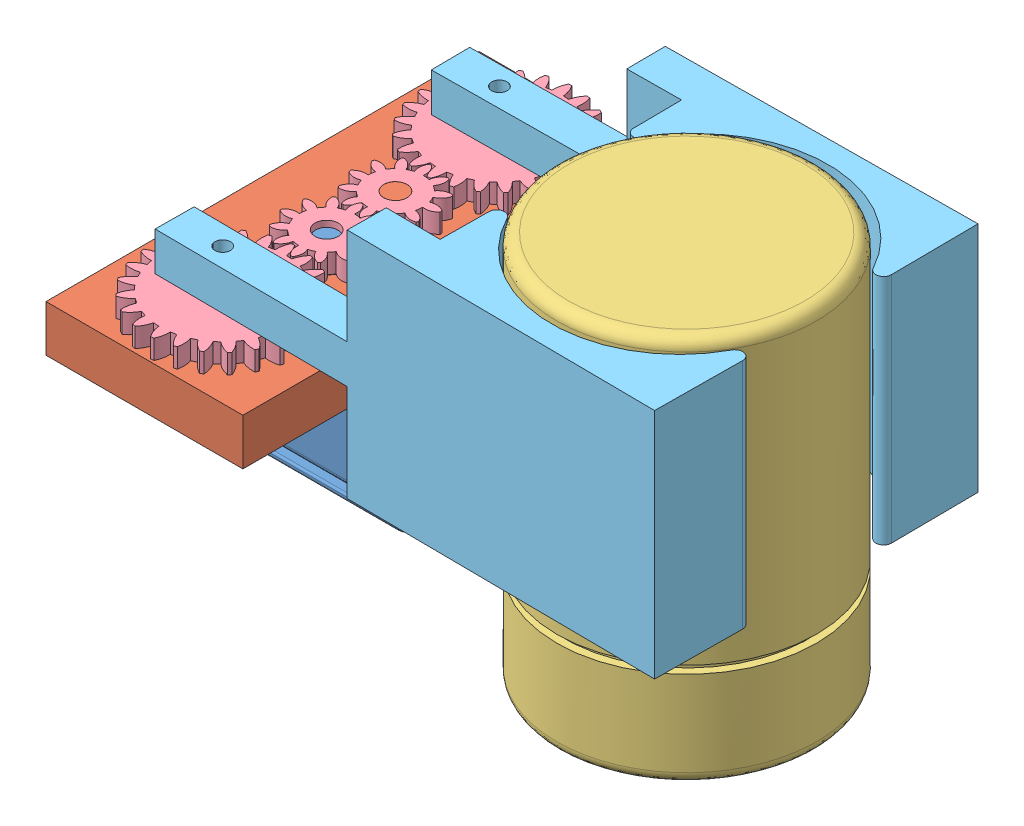
SolidWorks assembly Assembly, configuration Default. Lengths in mm.
Overall size (143.71 100 123.27).
9 component instances, 5 part files, 15 mates.
Components (placement in the parent):
- servo-1: servo [Default] at (15.8776 33.6405 0.8899) size (56.4 46.15 25.5)
- support_base_v2-1: support_base_v2 [Default] at (16.1776 39.2905 -9.1101) x (0 0 1) z (-1 0 0) size (111.75 39 65)
- Can-1: Can [Default] at (89.3289 -1.3077 2.2501) size (67 100 67)
- spur gear_iso-4: spur gear_iso [ISO - Spur gear 1.5M 12T 20PA 5FW ---S12A75H50L6.0N] at (5.0776 61.5405 10.8899) x (0 -1 0) z (0.991445 0 0.130526) size (5 20.42 20.42)
- spur gear_iso-5: spur gear_iso [ISO - Spur gear 1.5M 24T 20PA 5FW ---S24A75H50L6.0N] at (5.0776 61.2905 37.7099) x (0 -1 0) z (0.896873 0 -0.442289) size (5 38.77 38.77)
- spur gear_iso-6: spur gear_iso [ISO - Spur gear 1.5M 24T 20PA 5FW ---S24A75H50L6.0N] at (5.0776 61.2905 -33.6801) x (0 -1 0) z (0.438371 0 0.898794) size (5 38.77 38.77)
- spur gear_iso-7: spur gear_iso [ISO - Spur gear 1.5M 12T 20PA 5FW ---S12A75H50L6.0N] at (5.0776 61.2905 -6.8601) x (0 -1 0) z (0.130526 0 -0.991445) size (5 20.42 20.42)
- arm_left_v2-1: arm_left_v2 [Default] at (70.6307 36.2905 -24.98) x (0.008727 0 0.999962) z (-0.999962 0 0.008727) size (24.52 60 130)
- arm_left_v2-2: arm_left_v2 [Default] at (70.6306 96.2905 29.0097) x (0.008724 0 -0.999962) z (-0.999962 0 -0.008724) size (24.52 60 130)
Mates (geometry in assembly coordinates):
- Coincident3: coincident anti-aligned: circle of servo-1; circle of support_base_v2-1
- Coincident4: coincident anti-aligned: circle of servo-1; circle of support_base_v2-1
- Coincident5: coincident anti-aligned: line of servo-1 through (5.0776 60.0405 10.8899) axis (0 -1 0); line of spur gear_iso-4 through (5.0776 56.5405 10.8899) axis (0 1 0)
- Coincident6: coincident anti-aligned: plane of servo-1 through (5.0776 56.5405 10.8899) normal (0 1 0); plane of spur gear_iso-4 through (5.0776 56.5405 10.8899) normal (0 -1 0)
- Coincident7: coincident anti-aligned: line of support_base_v2-1 through (5.0776 61.2905 -6.8601) axis (0 -1 0); line of spur gear_iso-7 through (5.0776 56.2905 -6.8601) axis (0 1 0)
- Coincident8: coincident anti-aligned: plane of support_base_v2-1 through (-12.3224 56.2905 -4.1101) normal (0 1 0); plane of spur gear_iso-7 through (5.0776 56.2905 -6.8601) normal (0 -1 0)
- GearMate1: gear = 12 : 12 mm: line of spur gear_iso-7 through (5.0776 56.2905 -6.8601) axis (0 1 0); line of spur gear_iso-4 through (5.0776 56.5405 10.8899) axis (0 1 0)
- Coincident9: coincident anti-aligned: line of support_base_v2-1 through (5.0776 61.2905 37.7099) axis (0 -1 0); line of spur gear_iso-5 through (5.0776 56.2905 37.7099) axis (0 1 0)
- Coincident10: coincident anti-aligned: plane of support_base_v2-1 through (-12.3224 56.2905 -4.1101) normal (0 1 0); plane of spur gear_iso-5 through (5.0776 56.2905 37.7099) normal (0 -1 0)
- GearMate3: gear = 24 : 12 mm: line of spur gear_iso-4 through (5.0776 56.5405 10.8899) axis (0 1 0); line of spur gear_iso-5 through (5.0776 56.2905 37.7099) axis (0 1 0)
- GearMate4: gear = 24 : 12 mm: line of spur gear_iso-7 through (5.0776 56.2905 -6.8601) axis (0 1 0); line of spur gear_iso-6 through (5.0776 56.2905 -33.6801) axis (0 1 0)
- Coincident13: coincident anti-aligned: line of support_base_v2-1 through (5.0776 61.2905 -33.6801) axis (0 -1 0); line of spur gear_iso-6 through (5.0776 56.2905 -33.6801) axis (0 1 0)
- Coincident14: coincident anti-aligned: plane of support_base_v2-1 through (-12.3224 56.2905 -4.1101) normal (0 1 0); plane of spur gear_iso-6 through (5.0776 56.2905 -33.6801) normal (0 -1 0)
- GearMate5: gear = 1 : 1 mm: line of spur gear_iso-6 through (5.0776 56.2905 -33.6801) axis (0 1 0); line of arm_left_v2-1 through (5.0776 61.2905 -33.6801) axis (0 1 0)
- GearMate6: gear = 1 : 1 mm: line of spur gear_iso-5 through (5.0776 56.2905 37.7099) axis (0 1 0); line of arm_left_v2-2 through (5.0776 71.2905 37.7099) axis (0 -1 0)
